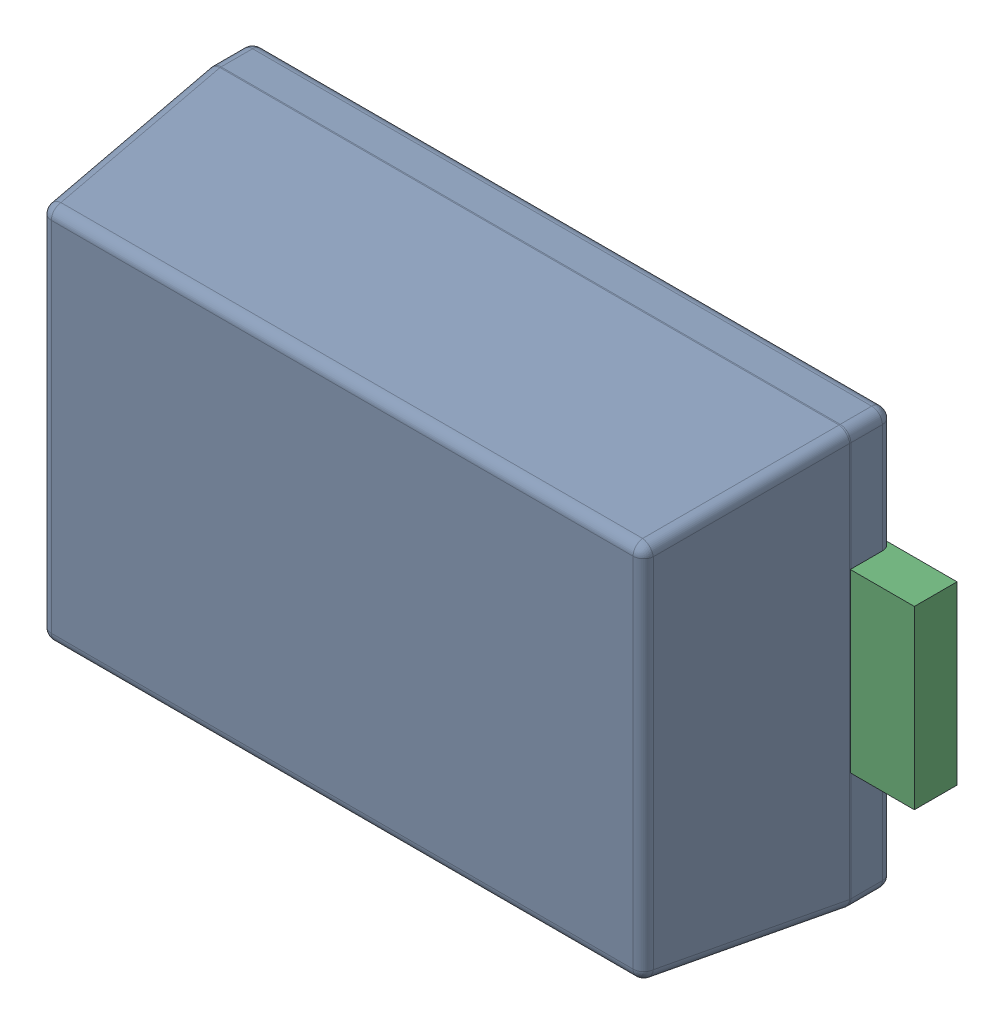
SolidWorks assembly 809573488, configuration Default. Lengths in mm.
Overall size (3.6 1.96 1.08).
4 component instances, 2 part files, 0 mates.
Components (placement in the parent):
- Body_4-1: Body_4 [Default] at (-1.5 -0.975 0) size (3.01 1.96 1.08)
  - Open_CASCADE_STEP_translator_6.8_1.1.1_3-1: Open_CASCADE_STEP_translator_6.8_1.1.1_3 [Default] at origin size (3.01 1.96 1.08)
- lead_3-1: lead_3 [Default] at (-1.8 -0.4125 0) size (0.68 0.82 0.2)
- lead_3-2: lead_3 [Default] at (1.8 0.4125 0) x (-1 0 0) z (0 0 1) size (0.68 0.82 0.2)
